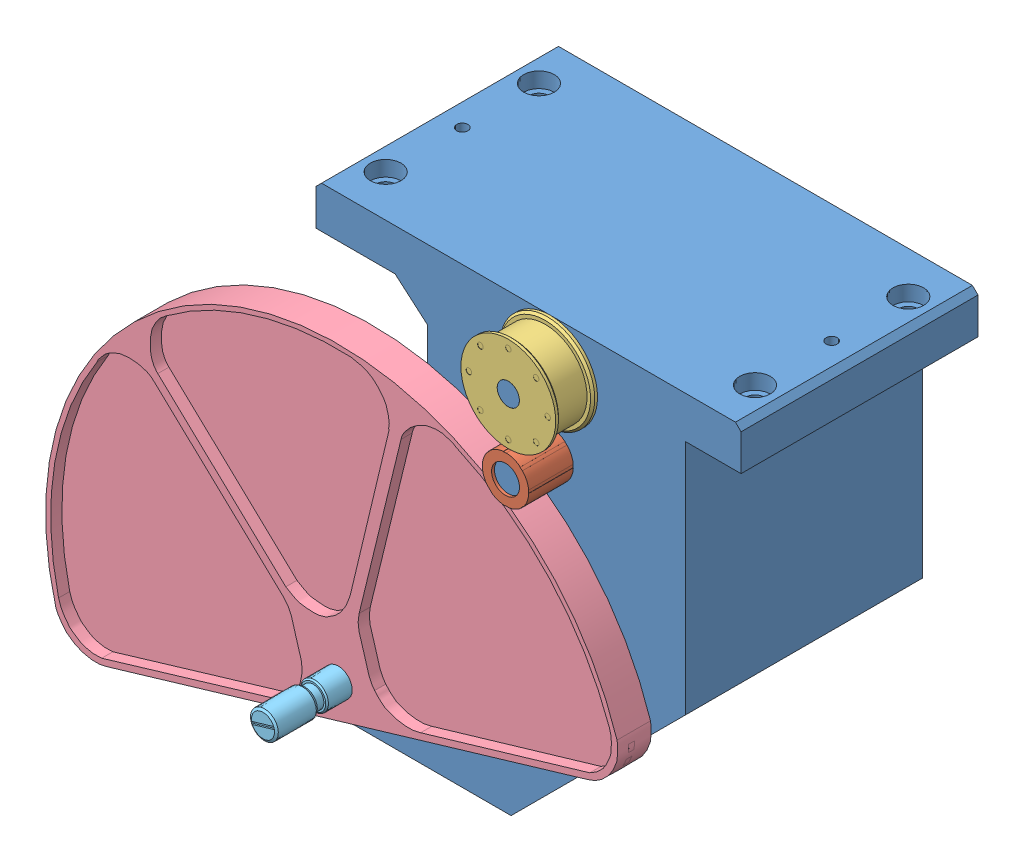
SolidWorks assembly BlocMoteur, configuration Défaut. Lengths in mm.
Overall size (260.5 181.1 163).
5 component instances, 5 part files, 10 mates.
Components (placement in the parent):
- Pièce1_BlocMoteur-1: Pièce1_BlocMoteur [Défaut] at origin size (152.5 162.5 100)
- Pièce1_PignionModifie-1: Pièce1_PignionModifie [Défaut] x (-0.683299 0.730139 0) z (0 0 1) size (16.65 16.65 16)
- Pièce1_poulie_renvoie-1: Pièce1_poulie_renvoie [Défaut] at (0 26 0) size (34 34 15)
- Pièce1_Roue-5: Pièce1_Roue [Défaut] at (-64 -97 0) x (0.958703 0.284409 0) z (0 0 1) size (209.95 116.72 12)
- Pièce1_arbre-5: Pièce1_arbre [Défaut] at (-64 -97 -42.5) x (0.958703 0.284409 0) z (0 0 1) size (15 15 163)
Mates (geometry in assembly coordinates):
- Coïncidente1: coincident anti-aligned: plane of Pièce1_BlocMoteur-1 through (0 0 0) normal (0 0 1); plane of Pièce1_PignionModifie-1 through (0 0 0) normal (0 0 -1)
- Coaxiale2: concentric aligned: cylinder of Pièce1_BlocMoteur-1 through (0 0 15) axis (0 0 -1) radius 5; cylinder of Pièce1_PignionModifie-1 through (0 0 16) axis (0 0 -1) radius 5
- Coïncidente2: coincident anti-aligned: plane of Pièce1_BlocMoteur-1 through (0 0 0) normal (0 0 1); plane of Pièce1_poulie_renvoie-1 through (0 26 0) normal (0 0 -1)
- Coïncidente5: coincident anti-aligned: plane of Pièce1_BlocMoteur-1 through (0 0 0) normal (0 0 1); plane of Pièce1_poulie_renvoie-1 through (0 26 0) normal (0 0 -1)
- Coaxiale4: concentric anti-aligned: cylinder of Pièce1_BlocMoteur-1 through (0 26 15) axis (0 0 -1) radius 4; cylinder of Pièce1_poulie_renvoie-1 through (0 26 15) axis (0 0 1) radius 4
- Coaxiale12: concentric anti-aligned: cylinder of Pièce1_BlocMoteur-1 through (-64 -97 -85) axis (0 0 1) radius 5; cylinder of Pièce1_Roue-5 through (-64 -97 12) axis (0 0 -1) radius 5
- Coïncidente17: coincident anti-aligned: plane of Pièce1_BlocMoteur-1 through (0 0 0) normal (0 0 1); plane of Pièce1_Roue-5 through (-64 -97 0) normal (0 0 -1)
- Coïncidente18: coincident aligned: plane of Pièce1_BlocMoteur-1 through (0 0 0) normal (0 0 1); plane of Pièce1_arbre-5 through (-64 -97 0) normal (0 0 1)
- Coaxiale13: concentric anti-aligned: cylinder of Pièce1_Roue-5 through (-64 -97 12) axis (0 0 -1) radius 5; cylinder of Pièce1_arbre-5 through (-64 -97 0) axis (0 0 1) radius 5
- Parallèle5: parallel aligned: plane of Pièce1_Roue-5 through (-60.702 -108.1172 12) normal (0.284409 -0.958703 0); plane of Pièce1_arbre-5 through (-68.0666 -97.7432 38.4) normal (0.284409 -0.958703 0)
